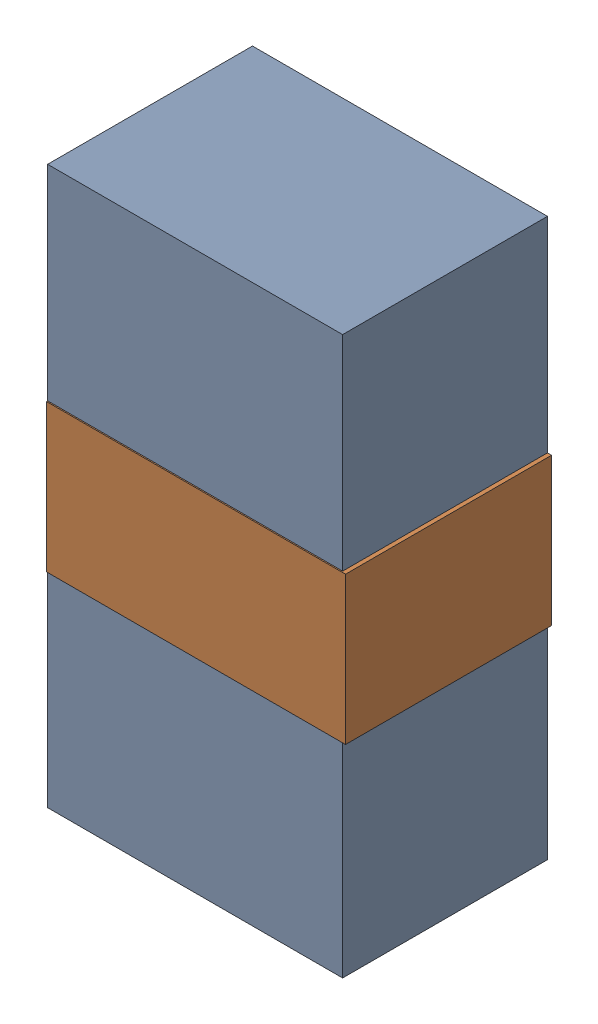
SolidWorks assembly LED2_Motor_10Kanaloa_v2.0.0_Motor, configuration Default. Lengths in mm.
Overall size (1.83 3.4 1.26).
4 component instances, 2 part files, 0 mates.
Components (placement in the parent):
- 334788016-1: 334788016 [Default] at (85.3315 173.482 0) size (1.8 3.4 1.25)
  - Extruded_12-1: Extruded_12 [Default] at origin size (1.8 3.4 1.25)
- 334787760-1: 334787760 [Default] at (85.344 173.482 0) size (1.83 0.9 1.26)
  - Extruded_13-1: Extruded_13 [Default] at origin size (1.83 0.9 1.26)
